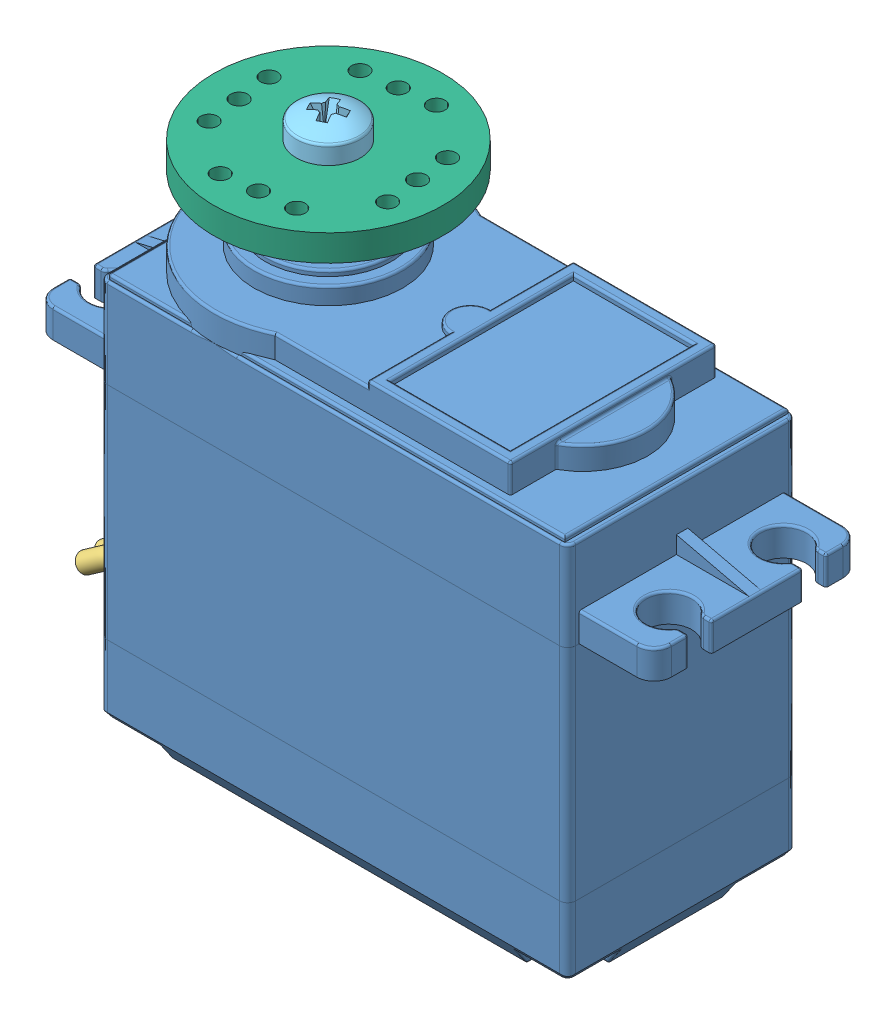
SolidWorks assembly MG996R Servo Motor, configuration Default. Lengths in mm.
Overall size (57.44 47.35 22.27).
9 component instances, 6 part files, 30 mates.
Components (placement in the parent):
- Case-1: Case [Default] at origin size (54 39 20)
- Output Shaft-1: Output Shaft [Default] at (-10.45 9.35 0) x (0.84541 0 0.534117) z (-0.534117 0 0.84541) size (13.78 15.2 13.78)
- Rubber Wire Cable Sleeve-1: Rubber Wire Cable Sleeve [Default] at (-18.2 -12.025 0) size (15.24 5.03 7.75)
- Pan Head Cross Screw M1.6-1: Pan Head Cross Screw M1.6 [Default] at (-17.575 12.35 7.125) x (0 1 0) z (0.509945 0 0.860207) size (32.17 3.2 3.2)
- Pan Head Cross Screw M1.6-2: Pan Head Cross Screw M1.6 [Default] at (17.575 12.35 7.125) x (0 1 0) z (0.498431 0 0.86693) size (32.17 3.2 3.2)
- Pan Head Cross Screw M1.6-3: Pan Head Cross Screw M1.6 [Default] at (17.575 12.35 -7.125) x (0 1 0) z (0.499198 0 0.866488) size (32.17 3.2 3.2)
- Pan Head Cross Screw M1.6-4: Pan Head Cross Screw M1.6 [Default] at (-17.575 12.35 -7.125) x (0 1 0) z (0.500246 0 0.865884) size (32.17 3.2 3.2)
- Pan Head Cross Screw M3-1: Pan Head Cross Screw M3 [Default] at (-10.45 20.85 0) x (0 -1 0) z (0.893136 0 -0.449786) size (8.51 5.6 5.6)
- Servo Horns-6: Servo Horns [Circular Horn] at (-10.45 25.7 0) x (0.120731 0 0.992685) z (0.992685 0 -0.120731) size (20 5.5 20)
Mates (geometry in assembly coordinates):
- Concentric1: concentric aligned: cylinder of Case-1 through (-10.45 -18.151 0) axis (0 1 0) radius 3.25; cylinder of Output Shaft-1 through (-10.45 14.8629 0) axis (0 1 0) radius 3
- Distance1: distance = 3.7 mm aligned: plane of Output Shaft-1 through (-8.9705 24.55 0.9347) normal (0 1 0); plane of Case-1 through (-10.45 20.85 0) normal (0 1 0)
- Coincident1: coincident anti-aligned: plane of Case-1 through (0 -13.4 0) normal (0 1 0); plane of Rubber Wire Cable Sleeve-1 through (-20.45 -13.4 2.9) normal (0 -1 0)
- Coincident2: coincident anti-aligned: plane of Case-1 through (-20.45 -13.4 -2.9) normal (0 0 1); plane of Rubber Wire Cable Sleeve-1 through (-20.45 -13.4 -2.9) normal (0 0 -1)
- Coincident4: coincident anti-aligned: plane of Case-1 through (-20.45 -18.15 10) normal (-1 0 0); plane of Rubber Wire Cable Sleeve-1 through (-20.45 -12.025 0) normal (1 0 0)
- Concentric2: concentric aligned: cylinder of Case-1 through (-17.575 19.632 7.125) axis (0 -1 0) radius 1.125; cylinder of Pan Head Cross Screw-1 through (-17.575 9.998 7.125) axis (0 -1 0) radius 1.6
- Screw1: screw = 0.35 mm aligned: cylinder of Case-1 through (-17.575 16.632 7.125) axis (0 -1 0) radius 0.8; cylinder of Pan Head Cross Screw-1 through (-17.575 9.998 7.125) axis (0 -1 0) radius 0.8
- Coincident5: coincident anti-aligned: plane of Case-1 through (-17.575 -16.65 7.125) normal (0 -1 0); plane of Pan Head Cross Screw-1 through (-17.167 -16.65 7.8132) normal (0 1 0)
- Concentric3: concentric aligned: cylinder of Case-1 through (17.575 19.632 7.125) axis (0 -1 0) radius 1.125; cylinder of Pan Head Cross Screw-2 through (17.575 9.998 7.125) axis (0 -1 0) radius 1.6
- Screw2: screw = 0.35 mm aligned: cylinder of Case-1 through (17.575 16.632 7.125) axis (0 -1 0) radius 0.8; cylinder of Pan Head Cross Screw-2 through (17.575 9.998 7.125) axis (0 -1 0) radius 0.8
- Coincident6: coincident anti-aligned: plane of Case-1 through (17.575 -16.65 7.125) normal (0 -1 0); plane of Pan Head Cross Screw-2 through (17.9737 -16.65 7.8185) normal (0 1 0)
- Concentric4: concentric aligned: cylinder of Case-1 through (17.575 19.632 -7.125) axis (0 -1 0) radius 1.125; cylinder of Pan Head Cross Screw-3 through (17.575 9.998 -7.125) axis (0 -1 0) radius 1.6
- Screw3: screw = 0.35 mm aligned: cylinder of Case-1 through (17.575 16.632 -7.125) axis (0 -1 0) radius 0.8; cylinder of Pan Head Cross Screw-3 through (17.575 9.998 -7.125) axis (0 -1 0) radius 0.8
- Coincident7: coincident anti-aligned: plane of Case-1 through (17.575 -16.65 -7.125) normal (0 -1 0); plane of Pan Head Cross Screw-3 through (17.9744 -16.65 -6.4318) normal (0 1 0)
- Concentric5: concentric aligned: cylinder of Case-1 through (-17.575 19.632 -7.125) axis (0 -1 0) radius 1.125; cylinder of Pan Head Cross Screw-4 through (-17.575 9.998 -7.125) axis (0 -1 0) radius 1.6
- Screw4: screw = 0.35 mm aligned: cylinder of Case-1 through (-17.575 16.632 -7.125) axis (0 -1 0) radius 0.8; cylinder of Pan Head Cross Screw-4 through (-17.575 9.998 -7.125) axis (0 -1 0) radius 0.8
- Coincident8: coincident anti-aligned: plane of Case-1 through (-17.575 -16.65 -7.125) normal (0 -1 0); plane of Pan Head Cross Screw-4 through (-17.1748 -16.65 -6.4323) normal (0 1 0)
- Concentric6: concentric aligned: cylinder of Output Shaft-1 through (-10.45 14.8629 0) axis (0 1 0) radius 2.5; cylinder of Servo Horns-1 through (-10.45 24.55 0) axis (0 1 0) radius 1.5
- Coincident9: coincident anti-aligned: plane of Output Shaft-1; plane of Servo Horns-1 through (-10.1667 21.35 -2.8861) normal (-0.731335 0 0.682019)
- Coincident10: coincident anti-aligned: plane of Output Shaft-1; plane of Servo Horns-1 through (-10.45 24.55 0) normal (0 -1 0)
- Concentric7: concentric aligned: cylinder of Servo Horns-1 through (-10.45 24.55 0) axis (0 1 0) radius 1.5; cylinder of Pan Head Cross Screw M3-1 through (-10.45 23.202 0) axis (0 1 0) radius 2.8
- Screw5: screw = 0.5 mm aligned: cylinder of Output Shaft-1 through (-10.45 14.8629 0) axis (0 1 0) radius 1.5; cylinder of Pan Head Cross Screw M3-1 through (-10.45 23.202 0) axis (0 1 0) radius 1.5
- Coincident11: coincident anti-aligned: plane of Servo Horns-1 through (-10.45 26.85 0) normal (0 1 0); plane of Pan Head Cross Screw M3-1
- Coincident12: coincident aligned: plane of Case-1 through (0 -18.15 0) normal (0 -1 0); plane of Servo Horns-2 through (-24.387 -18.15 16.7031) normal (0 -1 0)
- Coincident13: coincident aligned: plane of Case-1 through (0 -18.15 0) normal (0 -1 0); plane of Servo Horns-4 through (17.6195 -18.15 33.5795) normal (0 -1 0)
- Coincident14: coincident aligned: plane of Case-1 through (0 -18.15 0) normal (0 -1 0); plane of Servo Horns-2 through (-24.387 -18.15 16.7031) normal (0 -1 0)
- Coincident15: coincident aligned: plane of Case-1 through (0 -18.15 0) normal (0 -1 0); plane of Servo Horns-3 through (-23.734 -18.15 33.4052) normal (0 -1 0)
- Coincident17: coincident aligned: plane of Case-1 through (0 -18.15 0) normal (0 -1 0); plane of Servo Horns-5 through (-25.9857 -18.15 59.7933) normal (0 -1 0)
- Concentric8: concentric aligned: cylinder of Pan Head Cross Screw M3-1 through (-10.45 23.202 0) axis (0 1 0) radius 2.8; cylinder of Servo Horns-6 through (-10.45 21.35 0) axis (0 1 0) radius 4.4
- Coincident20: coincident anti-aligned: plane of Output Shaft-1 through (-8.9705 24.55 0.9347) normal (0 1 0); plane of Servo Horns-6 through (-10.45 24.55 0) normal (0 -1 0)
